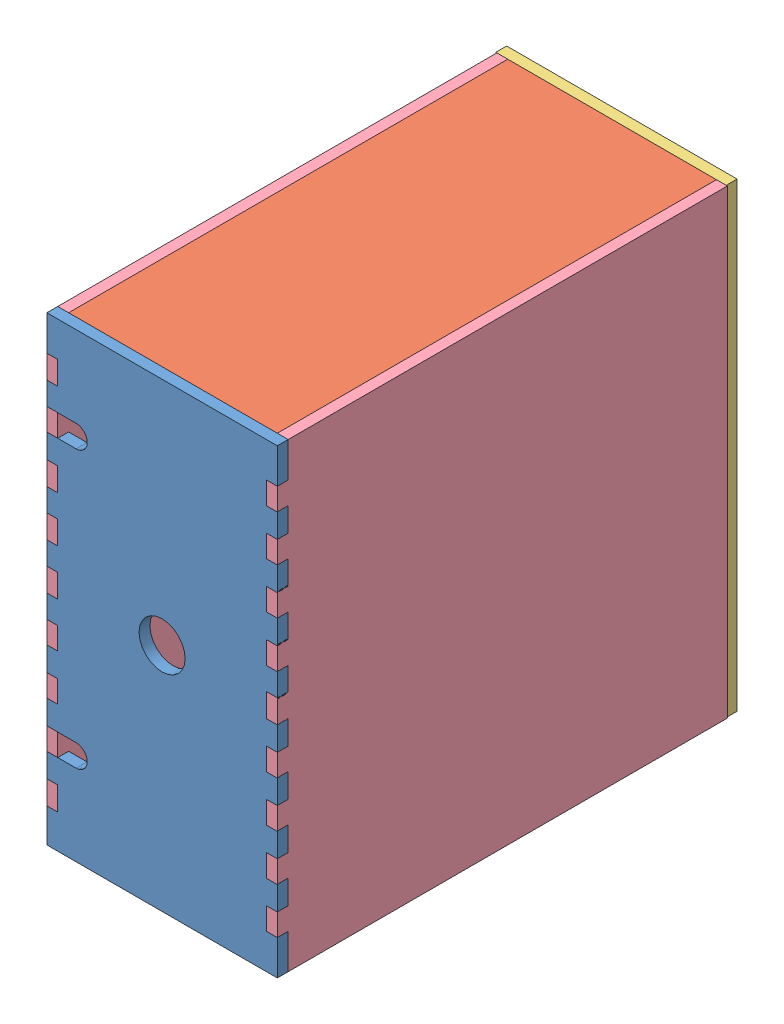
SolidWorks assembly elecbox, configuration Default. Lengths in mm.
Overall size (63.8 127 127).
6 component instances, 4 part files, 13 mates.
Components (placement in the parent):
- elecfront-1: elecfront [Default] at (-110.9975 67.0619 15.6167) size (63.5 127 3)
- elecbottom-1: elecbottom [Default] at (-108.0003 -59.9381 15.6167) x (0 0 -1) z (1 0 0) size (121.01 3 57.51)
- elecbottom-2: elecbottom [Default] at (-108.0003 64.0647 15.6167) x (0 0 -1) z (1 0 0) size (121.01 3 57.51)
- elecback-1: elecback [Default] at (-111.2962 67.0619 -108.3861) size (63.5 127 3)
- elecside-1: elecside [Default] at (-47.4975 67.0619 -105.3889) x (-1 0 0) z (0 0 -1) size (3 127 124)
- elecside-2: elecside [Default] at (-110.9975 -59.9381 -105.3889) x (1 0 0) z (0 0 -1) size (3 127 124)
Mates (geometry in assembly coordinates):
- Coincident1: coincident anti-aligned: plane of elecfront-1 through (-102.9203 -34.5381 15.6167) normal (0 0 -1); plane of elecbottom-1 through (-108.0003 -56.9409 15.6167) normal (0 0 1)
- Coincident3: coincident aligned: plane of elecfront-1 through (-110.9975 -59.9381 18.6139) normal (0 -1 0); plane of elecbottom-1 through (-108.0003 -59.9381 15.6167) normal (0 -1 0)
- Coincident5: coincident anti-aligned: plane of elecfront-1 through (-102.9203 -34.5381 15.6167) normal (0 0 -1); plane of elecbottom-2 through (-108.0003 67.0619 15.6167) normal (0 0 1)
- Coincident6: coincident: plane of elecfront-1 through (-110.9975 67.0619 18.6139) normal (0 1 0); plane of elecbottom-2 through (-108.0003 67.0619 15.6167) normal (0 1 0)
- Coincident7: coincident: plane of elecfront-1 through (-108.0003 57.4099 18.6139) normal (-1 0 0); plane of elecbottom-2 through (-108.0003 67.0619 15.6167) normal (-1 0 0)
- Coincident9: coincident: plane of elecbottom-1 through (-108.0003 -56.9409 -105.3889) normal (0 0 -1); plane of elecback-1 through (-111.2962 67.0619 -105.3889) normal (0 0 1)
- Coincident10: coincident aligned: plane of elecbottom-1 through (-108.0003 -59.9381 15.6167) normal (0 -1 0); plane of elecback-1 through (-111.2962 -59.9381 -105.3889) normal (0 -1 0)
- Coincident18: coincident anti-aligned: plane of elecbottom-2 through (-50.4947 67.0619 15.6167) normal (1 0 0); plane of elecside-1 through (-50.4947 67.0619 -105.3889) normal (-1 0 0)
- Coincident19: coincident: plane of elecback-1 through (-111.2962 67.0619 -105.3889) normal (0 0 1); plane of elecside-1 through (-50.4947 67.0619 -105.3889) normal (0 0 -1)
- Coincident20: coincident aligned: plane of elecbottom-2 through (-108.0003 67.0619 15.6167) normal (0 1 0); plane of elecside-1 through (-50.4947 67.0619 -105.3889) normal (0 1 0)
- Coincident22: coincident anti-aligned: plane of elecbottom-1 through (-108.0003 -56.9409 15.6167) normal (-1 0 0); plane of elecside-2 through (-108.0003 -59.9381 -105.3889) normal (1 0 0)
- Coincident23: coincident aligned: plane of elecbottom-1 through (-108.0003 -59.9381 15.6167) normal (0 -1 0); plane of elecside-2 through (-108.0003 -59.9381 -105.3889) normal (0 -1 0)
- Coincident24: coincident: plane of elecback-1 through (-111.2962 67.0619 -105.3889) normal (0 0 1); plane of elecside-2 through (-108.0003 -59.9381 -105.3889) normal (0 0 -1)
